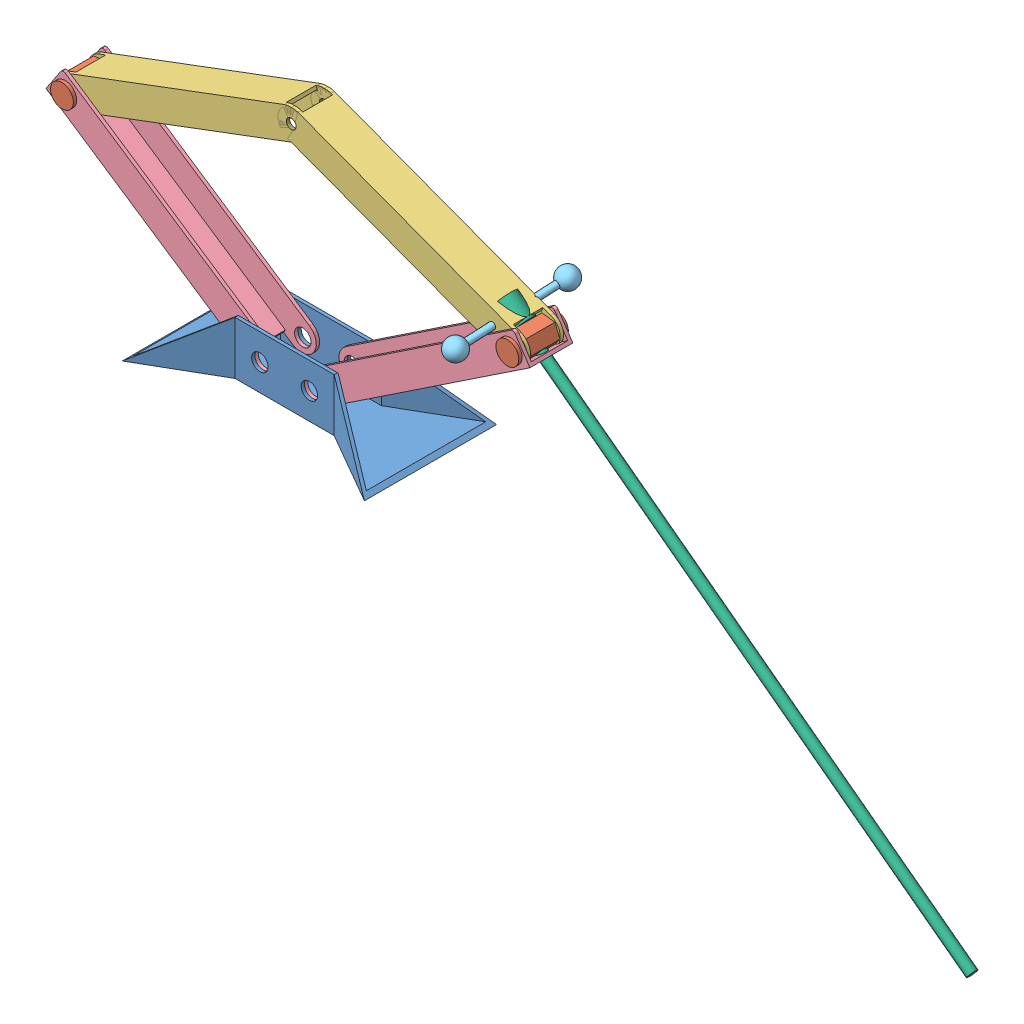
SolidWorks assembly final, configuration Default. Lengths in mm.
Overall size (1411.2 936.71 389.87).
12 component instances, 6 part files, 9 mates.
Components (placement in the parent):
- Foot-1: Foot [Default] at (133.4039 131.7253 296.3944) size (366.51 80 200)
- major-1: major [Default] at (533.02 394.5177 261.6988) x (0 0 1) z (-0.60015 -0.799888 0) size (75 398.91 393.06)
  - Pin-1: Pin [Default] at (34.6956 36.1979 56.0316) size (75 34.64 40)
  - Arm - Upper-1: Arm - Upper [Default] at (34.6956 213.8718 89.7693) x (0 -0.959783 -0.280744) z (-1 0 0) size (400 45 55)
  - Arm - Lower-1: Arm - Lower [Default] at (34.6956 79.5672 231.6031) x (0 0.332627 0.943059) z (-1 0 0) size (400 45 65)
- major2-1: major2 [Default] at (442.0854 391.6533 299.1334) x (-0.455128 0.880689 0.131324) z (-0.174809 -0.232988 0.956639) size (805.73 430.25 180)
  - Pin - Handle-1: Pin - Handle [Default] at origin size (30 30 180)
  - Screw-1: Screw [Default] at (-15.6204 -7.89 -2.8632) x (0.892596 0.450857 0) z (0 0 1) size (885 35 35)
- major-2: major [Default] at (-266.2121 394.5177 331.09) x (0 0 -1) z (0.60015 -0.799888 0) size (75 398.91 393.06)
  - Pin-1: Pin [Default] at (34.6956 36.1979 56.0316) size (75 34.64 40)
  - Arm - Upper-1: Arm - Upper [Default] at (34.6956 213.8718 89.7693) x (0 -0.959783 -0.280744) z (-1 0 0) size (400 45 55)
  - Arm - Lower-1: Arm - Lower [Default] at (34.6956 79.5672 231.6031) x (0 0.332627 0.943059) z (-1 0 0) size (400 45 65)
Mates (geometry in assembly coordinates):
- Coincident1: coincident anti-aligned: circle of Foot-1; circle of major-1/Arm - Lower-1
- Parallel1: parallel anti-aligned: plane of Foot-1 through (57.0642 211.7253 328.8944) normal (0 0 -1); plane of major-1/Arm - Lower-1 through (163.9706 146.0703 328.8944) normal (0 0 1)
- Concentric1: concentric aligned: cylinder of major-1/Pin-1 through (484.2929 361.028 296.3944) axis (-0.799888 0.60015 0) radius 7.5; cylinder of major2-1/Screw-1 through (1136.4885 -128.3094 296.3944) axis (-0.799888 0.60015 0) radius 7.5
- Coincident3: coincident: circle of major-1/Pin-1; circle of major2-1/Screw-1
- Coincident5: coincident anti-aligned: plane of major-1/Pin-1 through (462.5854 389.8166 318.8944) normal (-0.799888 0.60015 0); plane of major2-1/Screw-1 through (456.5839 381.8178 296.3944) normal (0.799888 -0.60015 0)
- Coincident6: coincident aligned: circle of Foot-1; circle of major-2/Arm - Lower-1
- Parallel2: parallel anti-aligned: plane of Foot-1 through (57.0642 211.7253 328.8944) normal (0 0 -1); plane of major-2/Arm - Lower-1 through (125.0258 179.3519 328.8944) normal (0 0 1)
- Coincident9: coincident anti-aligned: plane of Foot-1 through (57.0642 211.7253 328.8944) normal (0 0 -1); plane of major-2/Arm - Lower-1 through (125.0258 179.3519 328.8944) normal (0 0 1)
- Coincident10: coincident aligned: circle of major-1/Arm - Upper-1; circle of major-2/Arm - Upper-1
